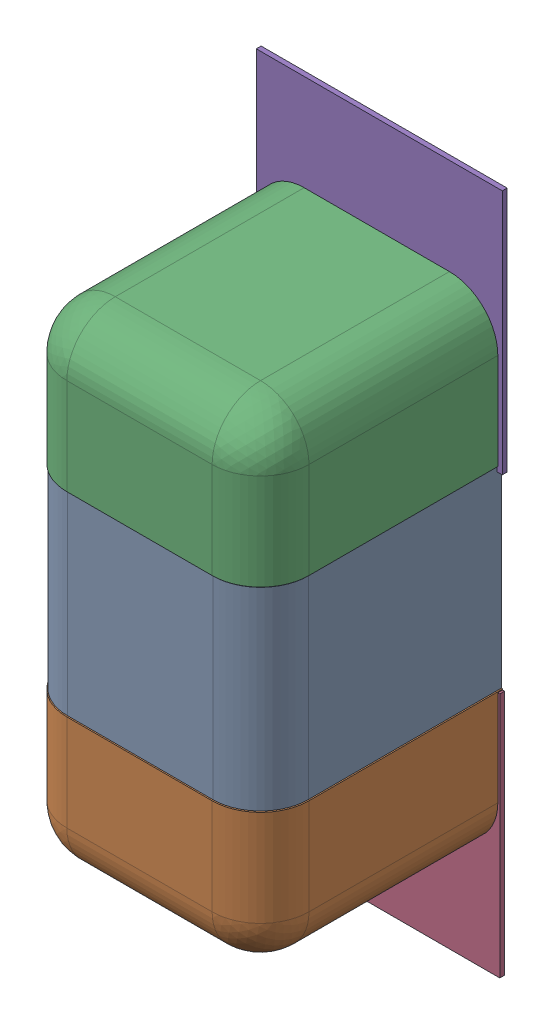
SolidWorks assembly C27, configuration Défaut. Lengths in mm.
Overall size (0.51 1.41 0.5).
8 component instances, 4 part files, 0 mates.
Components (placement in the parent):
- 6501216624-1: 6501216624 [Défaut] at (13.2588 -20.9804 0) x (0 1 0) z (1 0 0) size (1 0.5 0.5)
  - Open CASCADE STEP translator 7.5 2.111.1.1-1: Open CASCADE STEP translator 7.5 2.111.1.1 [Défaut] at origin size (0.4 0.5 0.5)
  - Open CASCADE STEP translator 7.5 2.111.1.2-1: Open CASCADE STEP translator 7.5 2.111.1.2 [Défaut] at origin size (0.3 0.5 0.5)
  - Open CASCADE STEP translator 7.5 2.111.1.3-1: Open CASCADE STEP translator 7.5 2.111.1.3 [Défaut] at origin size (0.3 0.5 0.5)
- 6504207776-1: 6504207776 [Défaut] at (13.2588 -21.4377 0) size (0.51 0.51 0.01)
  - Extruded-1: Extruded [Défaut] at origin size (0.51 0.51 0.01)
- 6504207776-2: 6504207776 [Défaut] at (13.264 -20.5354 0) size (0.51 0.51 0.01)
  - Extruded-1: Extruded [Défaut] at origin size (0.51 0.51 0.01)
